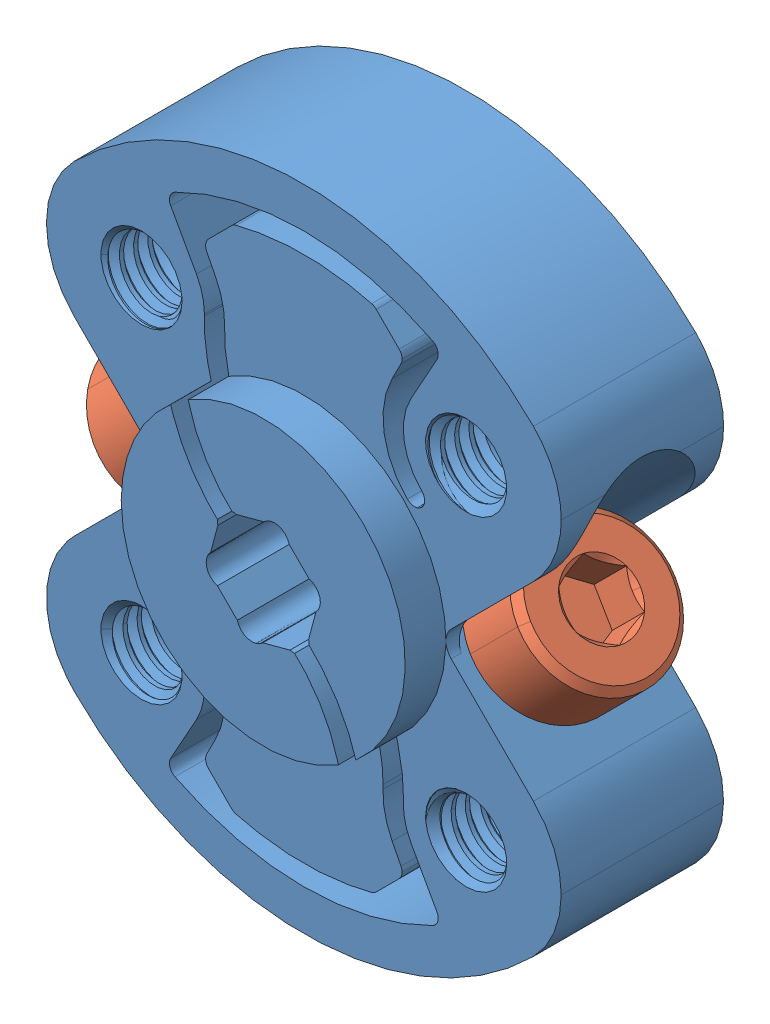
SolidWorks assembly 5mm Hex Hub 1309-0016-2005, configuration Default. Lengths in mm.
Overall size (27.74 32 10.95).
3 component instances, 2 part files, 0 mates.
Components (placement in the parent):
- 1309-0016-2005.STEP-1: 1309-0016-2005.STEP [Default] at (15.7004 -20.4917 -19.6976) size (25.38 32 10)
- 2800-0004-0014_90128A207.STEP-1: 2800-0004-0014_90128A207.STEP [Default] at (17.7533 -9.373 -19.6976) x (0.5 -0.5 -0.707107) z (0.707107 0.707107 0) size (7 7 18.01)
- 2800-0004-0014_90128A207.STEP-2: 2800-0004-0014_90128A207.STEP [Default] at (13.6476 -31.6104 -19.6976) x (-0.1284 0.1284 0.983375) z (-0.707107 -0.707107 0) size (7 7 18.01)
